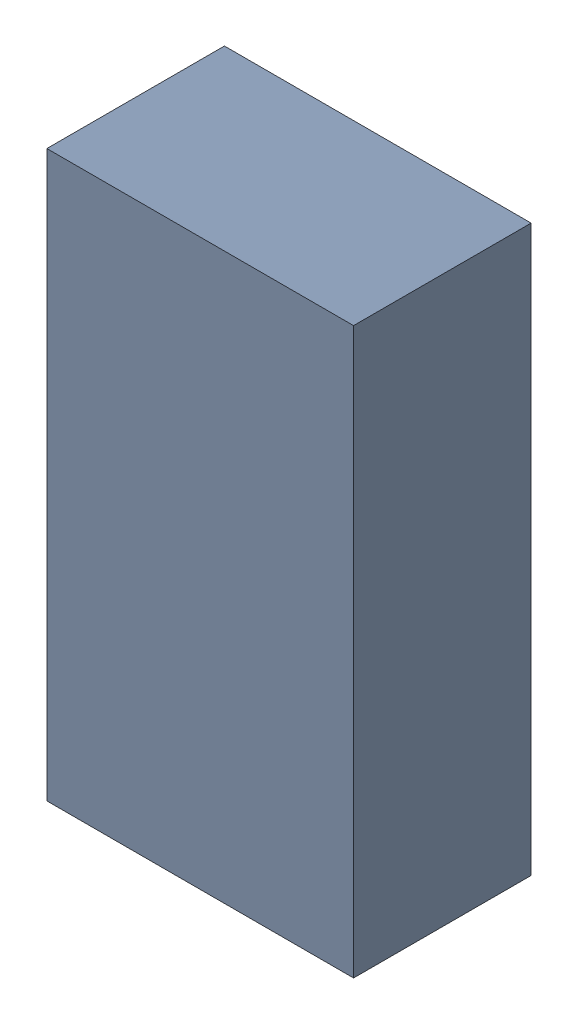
SolidWorks assembly L2_TDA1, configuration Standard. Lengths in mm.
Overall size (0.95 1.75 0.55).
2 component instances, 1 part files, 0 mates.
Components (placement in the parent):
- 885542784-1: 885542784 [Standard] at (1.84 59.87 0) size (0.95 1.75 0.55)
  - Extruded_22-1: Extruded_22 [Standard] at origin size (0.95 1.75 0.55)
